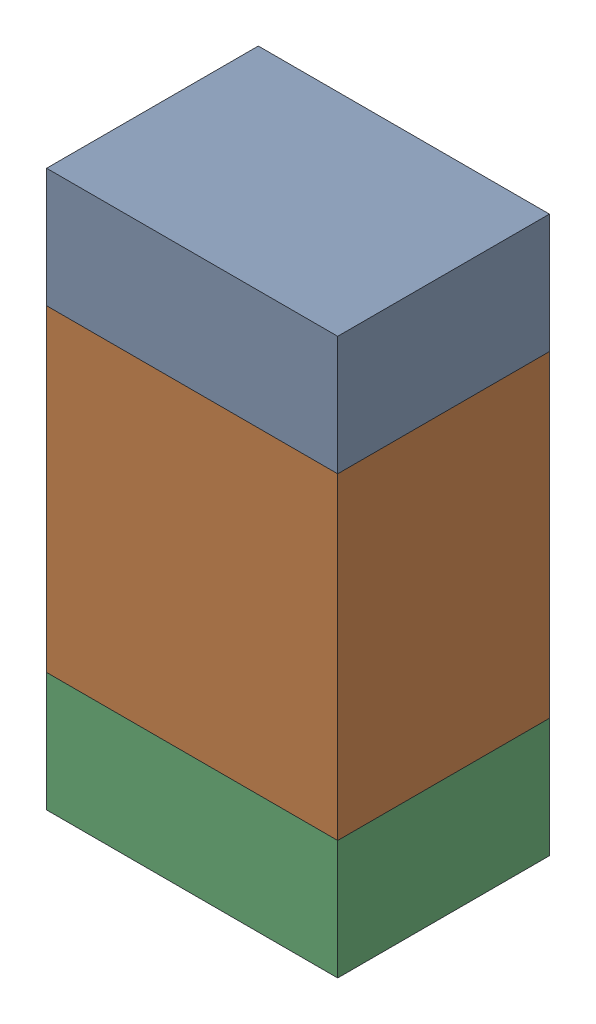
SolidWorks assembly R506_1PCB, configuration Default. Lengths in mm.
Overall size (0.55 1.05 0.4).
6 component instances, 2 part files, 0 mates.
Components (placement in the parent):
- 846483288-1: 846483288 [Default] at (147.1499 119.6626 0) size (0.55 0.22 0.4)
  - Extruded_12-1: Extruded_12 [Default] at origin size (0.55 0.22 0.4)
- 846483424-1: 846483424 [Default] at (147.1499 119.2501 0) size (0.55 0.6 0.4)
  - Extruded_13-1: Extruded_13 [Default] at origin size (0.55 0.6 0.4)
- 846483288-2: 846483288 [Default] at (147.1499 118.8376 0) size (0.55 0.22 0.4)
  - Extruded_12-1: Extruded_12 [Default] at origin size (0.55 0.22 0.4)
